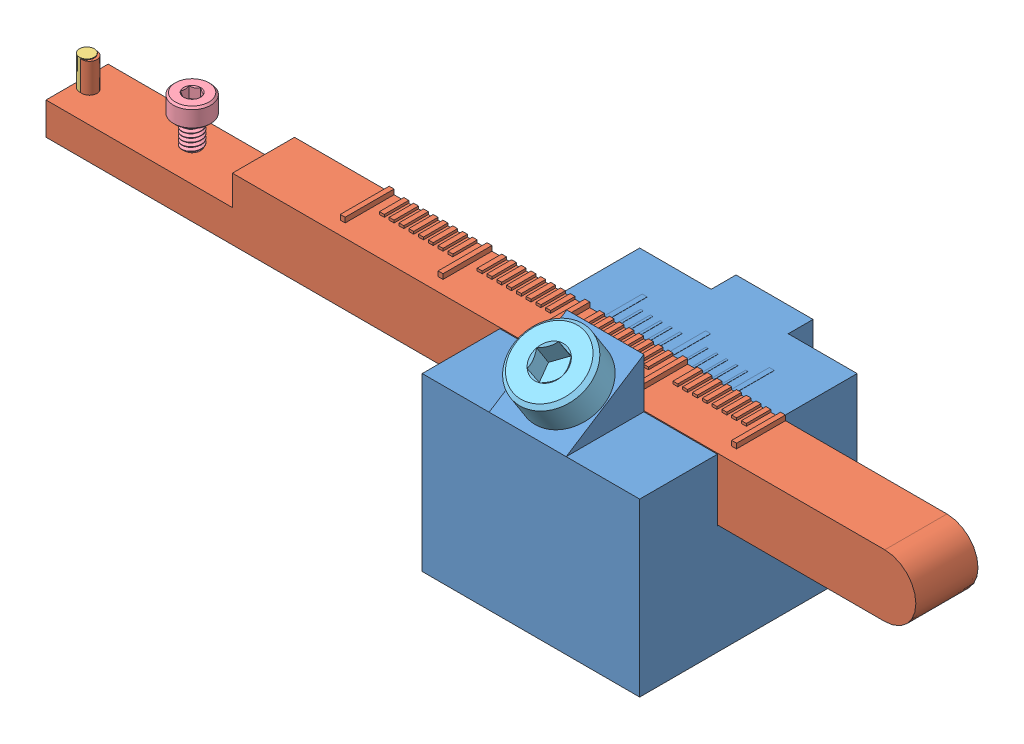
SolidWorks assembly headpost guide, configuration Default. Lengths in mm.
Overall size (88.9 25.48 26.59).
5 component instances, 5 part files, 3 mates.
Components (placement in the parent):
- bar rest-1: bar rest [Default] at origin size (22.23 22.61 24.77)
- headpost holder-1: headpost holder [Default] at (-46.4669 5.6081 -0.0801) x (0 1 0) z (1 0 0) size (6.86 6.35 88.9)
- headpost vertical pin-1: headpost vertical pin [Default] at (-45.4669 2.4571 -0.0801) size (1.52 6.35 1.52)
- 91292A003_TYPE 18-8 SS SOCKET HEAD CAP SCREW-1: 91292A003_TYPE 18-8 SS SOCKET HEAD CAP SCREW [91292A003] at (-34.7069 5.6982 -0.0801) x (1 0 0) z (0 -1 0) size (3.8 3.8 5.09)
- SOCKET CAP 2x-1: SOCKET CAP 2x [91292A003] at (10.7805 8.4439 5.3196) x (0.261996 0.520224 -0.81285) z (0 -0.842271 -0.539054) size (7.6 7.6 10.17)
Mates (geometry in assembly coordinates):
- Concentric1: concentric: circle of headpost holder-1; circle of headpost vertical pin-1
- Concentric2: concentric: circle of headpost holder-1; circle of 91292A003_TYPE 18-8 SS SOCKET HEAD CAP SCREW-1
- Concentric3: concentric anti-aligned: circle of bar rest-1; circle of SOCKET CAP 2x-1
